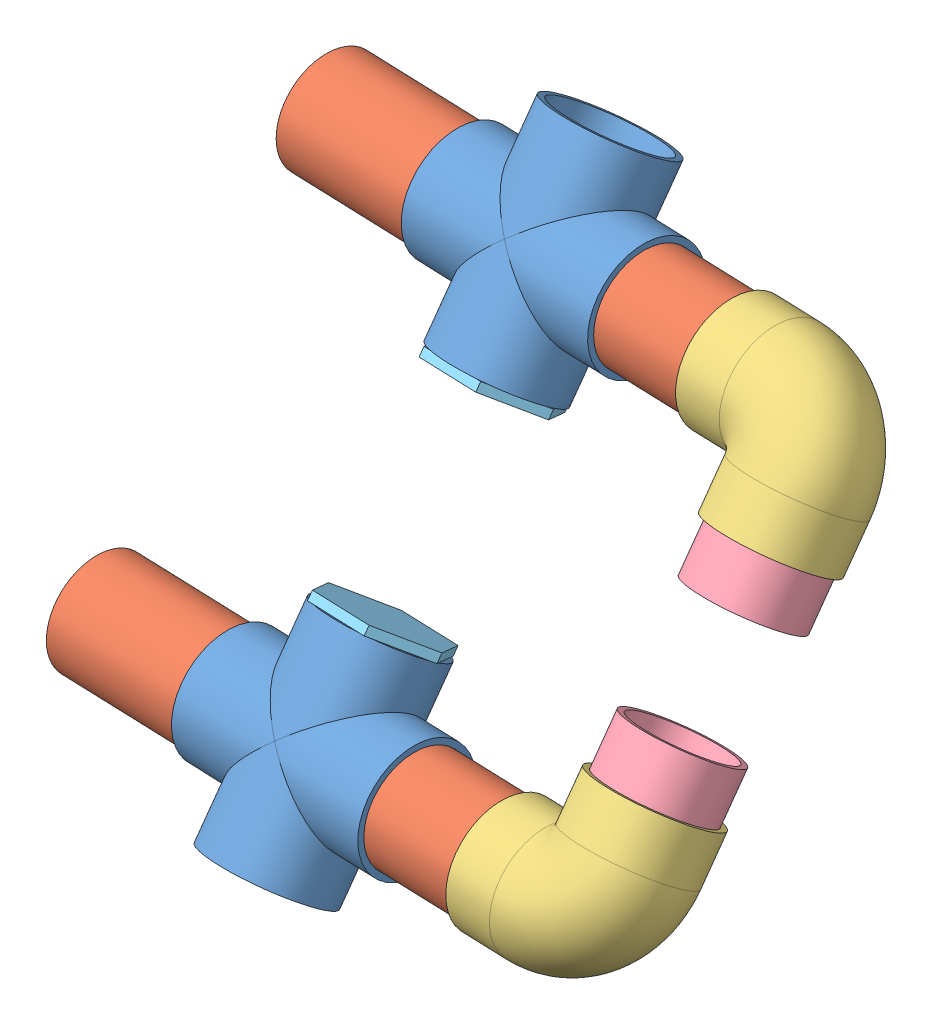
SolidWorks assembly PVC_frame, configuration Default. Lengths in mm.
Overall size (666.3 624.12 490.01).
12 component instances, 5 part files, 21 mates.
Components (placement in the parent):
- PVC_cross_fitting-1: PVC_cross_fitting [4880K249] at (-2323.5874 1031.1805 1268.7972) x (0.999015 0.008097 0.043621) z (-0.040602 0.563164 0.825347) size (219.96 219.96 127.76)
- PVC_pipe-1: PVC_pipe [48925K98] at (-2161.6899 1032.4926 1275.8662) x (-0.04361 -0.001535 0.999047) z (-0.999015 -0.008097 -0.043621) size (114.3 114.3 205.75)
- PVC_pipe-2: PVC_pipe [48925K98] at (-2485.4848 1029.8684 1261.7282) x (0.04361 0.001535 -0.999047) z (0.999015 0.008097 0.043621) size (114.3 114.3 205.75)
- PVC_pipe-3: PVC_pipe [48925K98] at (-2477.5068 1398.4997 1010.5901) x (0.04361 0.001535 -0.999047) z (0.999015 0.008097 0.043621) size (114.3 114.3 205.75)
- PVC_cross_fitting-3: PVC_cross_fitting [4880K249] at (-2315.6094 1399.8118 1017.6591) x (0.999015 0.008097 0.043621) z (-0.040602 0.563164 0.825347) size (219.96 219.96 127.76)
- PVC_pipe-4: PVC_pipe [48925K98] at (-2153.712 1401.124 1024.7281) x (0.04361 0.001535 -0.999047) z (0.999015 0.008097 0.043621) size (114.3 114.3 205.75)
- PVC_elbow (2)-3: PVC_elbow (2) [4880K28] at (-1992.0683 1402.434 1031.7861) x (0.999015 0.008097 0.043621) z (0.040602 -0.563164 -0.825347) size (173.99 173.99 127)
- PVC_pipe_2-3: PVC_pipe_2 [48925K98] at (-1994.0605 1310.3811 1094.4991) x (0.999706 -0.00556 0.023597) z (-0.017883 -0.826305 0.562938) size (114.3 114.3 104.95)
- PVC_pipe_2-4: PVC_pipe_2 [48925K98] at (-1998.054 1125.8556 1220.2111) x (0.999706 -0.00556 0.023597) z (-0.017883 -0.826305 0.562938) size (114.3 114.3 104.95)
- PVC_elbow (2)-4: PVC_elbow (2) [4880K28] at (-2000.0463 1033.8027 1282.9242) x (0.999015 0.008097 0.043621) z (-0.040602 0.563164 0.825347) size (173.99 173.99 127)
- PVC_end_cap-1: PVC_end_cap [4880K851] at (-2317.2072 1325.986 1067.9546) x (-0.017883 -0.826305 0.562938) z (-0.040602 0.563164 0.825347) size (60.32 133.82 115.89)
- PVC_end_cap-4: PVC_end_cap [4880K851] at (-2321.9896 1105.0064 1218.5018) x (0.017883 0.826305 -0.562938) z (-0.040602 0.563164 0.825347) size (60.32 133.82 115.89)
Mates (geometry in assembly coordinates):
- Concentric5: concentric aligned: circle of PVC_cross_fitting-1; circle of PVC_pipe-1
- Coincident3: coincident anti-aligned: plane of PVC_cross_fitting-1 through (-2264.4636 1031.6597 1271.3788) normal (0.999015 0.008097 0.043621); plane of PVC_pipe-1 through (-2264.4636 1031.6597 1271.3788) normal (-0.999015 -0.008097 -0.043621)
- Concentric9: concentric anti-aligned: circle of PVC_cross_fitting-1; circle of PVC_pipe-2
- Coincident4: coincident anti-aligned: plane of PVC_cross_fitting-1 through (-2382.7111 1030.7013 1266.2157) normal (-0.999015 -0.008097 -0.043621); plane of PVC_pipe-2 through (-2382.7111 1030.7013 1266.2157) normal (0.999015 0.008097 0.043621)
- Concentric18: concentric anti-aligned: circle of PVC_pipe-3; circle of PVC_cross_fitting-3
- Coincident13: coincident anti-aligned: plane of PVC_pipe-3 through (-2374.7331 1399.3327 1015.0776) normal (0.999015 0.008097 0.043621); plane of PVC_cross_fitting-3 through (-2374.7331 1399.3327 1015.0776) normal (-0.999015 -0.008097 -0.043621)
- Concentric19: concentric anti-aligned: circle of PVC_cross_fitting-3; circle of PVC_pipe-4
- Coincident14: coincident anti-aligned: plane of PVC_cross_fitting-3 through (-2256.4857 1400.291 1020.2407) normal (0.999015 0.008097 0.043621); plane of PVC_pipe-4 through (-2256.4857 1400.291 1020.2407) normal (-0.999015 -0.008097 -0.043621)
- Concentric20: concentric anti-aligned: circle of PVC_pipe-4; circle of PVC_elbow (2)-3
- Parallel3: parallel anti-aligned: plane of PVC_cross_fitting-3 through (-2249.8245 1491.2078 958.5325) normal (0.017883 0.826305 -0.562938); plane of PVC_elbow (2)-3 through (-1930.6067 1311.6497 1096.755) normal (-0.017883 -0.826305 0.562938)
- Coincident15: coincident anti-aligned: circle of PVC_pipe-4; plane of PVC_elbow (2)-3 through (-2050.9383 1401.9569 1029.2156) normal (-0.999015 -0.008097 -0.043621)
- Concentric21: concentric anti-aligned: circle of PVC_elbow (2)-3; circle of PVC_pipe_2-3
- Coincident16: coincident anti-aligned: plane of PVC_elbow (2)-3 through (-1993.1221 1353.7415 1064.9589) normal (-0.017883 -0.826305 0.562938); plane of PVC_pipe_2-3 through (-1993.1221 1353.7415 1064.9589) normal (0.017883 0.826305 -0.562938)
- Concentric25: concentric aligned: circle of PVC_pipe_2-4; circle of PVC_elbow (2)-4
- Coincident19: coincident anti-aligned: circle of PVC_pipe_2-4; plane of PVC_elbow (2)-4 through (-1998.9924 1082.4952 1249.7513) normal (0.017883 0.826305 -0.562938)
- Coincident26: coincident anti-aligned: plane of PVC_cross_fitting-3 through (-2316.6678 1350.9094 1050.9749) normal (-0.017883 -0.826305 0.562938); plane of PVC_end_cap-1 through (-2367.7476 1350.4955 1048.7446) normal (0.017883 0.826305 -0.562938)
- Concentric30: concentric anti-aligned: circle of PVC_cross_fitting-3; circle of PVC_end_cap-1
- Coincident28: coincident anti-aligned: plane of PVC_cross_fitting-1 through (-2322.529 1080.0829 1235.4814) normal (0.017883 0.826305 -0.562938); plane of PVC_end_cap-4 through (-2271.4492 1080.4969 1237.7117) normal (-0.017883 -0.826305 0.562938)
- Concentric32: concentric aligned: circle of PVC_cross_fitting-1; circle of PVC_end_cap-4
- Coincident40: coincident anti-aligned: plane of PVC_pipe-1 through (-2058.9162 1033.3256 1280.3537) normal (0.999015 0.008097 0.043621); plane of PVC_elbow (2)-4 through (-2058.9162 1033.3256 1280.3537) normal (-0.999015 -0.008097 -0.043621)
- Concentric34: concentric aligned: cylinder of PVC_pipe-1 through (-2264.4636 1031.6597 1271.3788) axis (0.999015 0.008097 0.043621) radius 51.1302; cone of PVC_elbow (2)-4 through (-2058.9162 1033.3256 1280.3537) axis (0.999015 0.008097 0.043621)
